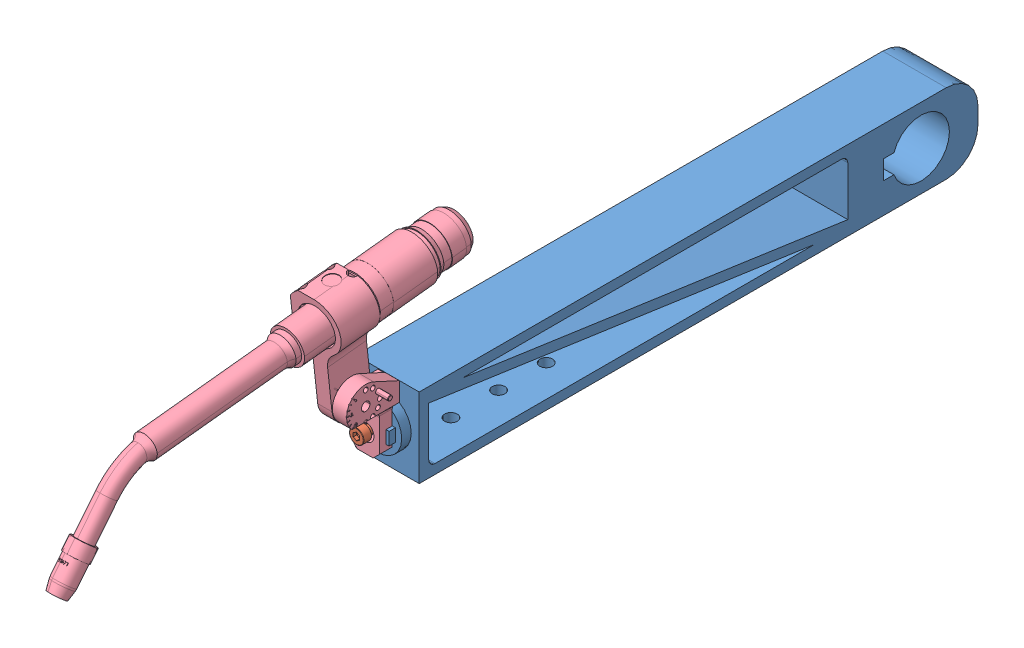
SolidWorks assembly khau3, configuration Default. Lengths in mm.
Overall size (20.65 60 283).
4 component instances, 4 part files, 3 mates.
Components (placement in the parent):
- khau3-1: khau3 [Default] at (66.2529 105.2782 132.2714) size (20 25 181)
- socket head cap screw_iso-2: socket head cap screw_iso [ISO 4762 M2.5 x 16 - 16N] at (76.2529 105.5186 230.0308) x (0 0 -1) z (0.999918 0.012841 0) size (18.5 4.5 4.5)
- hex thin nut chamfered gradeab_iso-2: hex thin nut chamfered gradeab_iso [ISO - 4035 - M2.5 - N] at (76.2529 105.2782 215.6714) x (-0.049946 -0.998752 0) z (0 0 -1) size (5 5.77 1.6)
- lapmohan1p-1: lapmohan1p [Default] at (69.7408 111.3116 218.5326) size (18.45 53.26 128.37)
Mates (geometry in assembly coordinates):
- Concentric1: concentric aligned: cylinder of socket head cap screw_iso-2 through (76.2529 105.5186 261.7808) axis (0 0 1) radius 1.25; cylinder of lapmohan1p-1 through (76.2529 105.5186 227.2714) axis (0 0 1) radius 1.45
- Coincident1: coincident anti-aligned: plane of khau3-1 through (76.2529 105.2782 223.2714) normal (0 0 1); plane of lapmohan1p-1 through (82.2529 111.9474 223.2714) normal (0 0 -1)
- Coincident2: coincident anti-aligned: plane of khau3-1 through (80.7529 103.2782 225.2714) normal (-1 0 0); plane of lapmohan1p-1 through (80.7529 111.8186 225.0214) normal (1 0 0)
